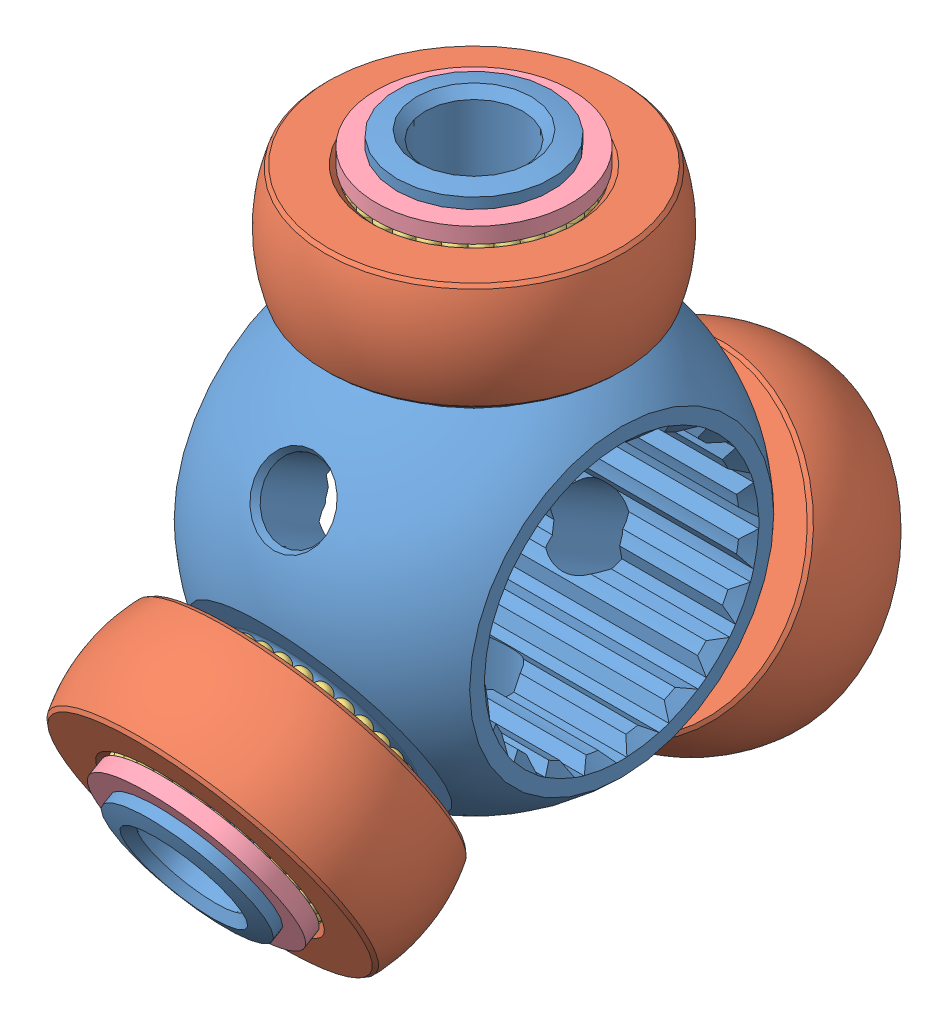
SolidWorks assembly EN-00031-AB-RCV Tripod, configuration Detailed. Lengths in mm.
Overall size (34.45 50.64 55.63).
94 component instances, 4 part files, 0 mates.
Components (placement in the parent):
- FSAE Tripod V2_1^EN-00031-AB-RCV Tripod-1: FSAE Tripod V2_1^EN-00031-AB-RCV Tripod [Default] at (-43.6945 4.946 19.6967) size (34.45 46.11 52.87) (virtual)
- FSAE roller_2451_2^EN-00031-AB-RCV Tripod-2: FSAE roller_2451_2^EN-00031-AB-RCV Tripod [Default] at (-43.6945 -7.4365 41.1438) x (0 0.5 -0.866025) z (1 0 0) size (8.74 25.48 25.48) (virtual)
- FSAE roller_2451_2^EN-00031-AB-RCV Tripod-3: FSAE roller_2451_2^EN-00031-AB-RCV Tripod [Default] at (-43.6945 -7.4365 -1.7504) x (0 0.5 0.866025) z (-1 0 0) size (8.74 25.48 25.48) (virtual)
- FSAE roller_2451_2^EN-00031-AB-RCV Tripod-4: FSAE roller_2451_2^EN-00031-AB-RCV Tripod [Default] at (-43.6945 29.711 19.6967) x (0 -1 0) z (-1 0 0) size (8.74 25.48 25.48) (virtual)
- needle^EN-00031-AB-RCV Tripod-1: needle^EN-00031-AB-RCV Tripod [Default] at (-42.3538 -7.5483 -1.6859) x (1 0 0) z (0 0.5 0.866025) size (1.5 1.5 10.16) (virtual)
- needle^EN-00031-AB-RCV Tripod-2: needle^EN-00031-AB-RCV Tripod [Default] at (-42.3574 -7.2961 -1.8314) x (0.976635 0.186114 -0.107453) z (0 0.5 0.866025) size (1.5 1.5 10.16) (virtual)
- needle^EN-00031-AB-RCV Tripod-3: needle^EN-00031-AB-RCV Tripod [Default] at (-42.4235 -7.0506 -1.9732) x (0.907631 0.363531 -0.209884) z (0 0.5 0.866025) size (1.5 1.5 10.16) (virtual)
- needle^EN-00031-AB-RCV Tripod-4: needle^EN-00031-AB-RCV Tripod [Default] at (-42.5489 -6.823 -2.1046) x (0.796213 0.523959 -0.302508) z (0 0.5 0.866025) size (1.5 1.5 10.16) (virtual)
- needle^EN-00031-AB-RCV Tripod-5: needle^EN-00031-AB-RCV Tripod [Default] at (-42.7279 -6.6242 -2.2194) x (0.647588 0.659903 -0.380995) z (0 0.5 0.866025) size (1.5 1.5 10.16) (virtual)
- needle^EN-00031-AB-RCV Tripod-6: needle^EN-00031-AB-RCV Tripod [Default] at (-42.9521 -6.4632 -2.3123) x (0.468701 0.76501 -0.441678) z (0 0.5 0.866025) size (1.5 1.5 10.16) (virtual)
- needle^EN-00031-AB-RCV Tripod-7: needle^EN-00031-AB-RCV Tripod [Default] at (-43.2109 -6.3478 -2.3789) x (0.267911 0.834367 -0.481722) z (0 0.5 0.866025) size (1.5 1.5 10.16) (virtual)
- needle^EN-00031-AB-RCV Tripod-8: needle^EN-00031-AB-RCV Tripod [Default] at (-43.4924 -6.2833 -2.4162) x (0.054602 0.864733 -0.499254) z (0 0.5 0.866025) size (1.5 1.5 10.16) (virtual)
- needle^EN-00031-AB-RCV Tripod-9: needle^EN-00031-AB-RCV Tripod [Default] at (-43.7833 -6.2726 -2.4224) x (-0.161259 0.854691 -0.493456) z (0 0.5 0.866025) size (1.5 1.5 10.16) (virtual)
- needle^EN-00031-AB-RCV Tripod-10: needle^EN-00031-AB-RCV Tripod [Default] at (-44.07 -6.3163 -2.3971) x (-0.369585 0.804708 -0.464599) z (0 0.5 0.866025) size (1.5 1.5 10.16) (virtual)
- needle^EN-00031-AB-RCV Tripod-11: needle^EN-00031-AB-RCV Tripod [Default] at (-44.3392 -6.4124 -2.3417) x (-0.560639 0.717121 -0.41403) z (0 0.5 0.866025) size (1.5 1.5 10.16) (virtual)
- needle^EN-00031-AB-RCV Tripod-12: needle^EN-00031-AB-RCV Tripod [Default] at (-44.5783 -6.5563 -2.2586) x (-0.725495 0.596023 -0.344114) z (0 0.5 0.866025) size (1.5 1.5 10.16) (virtual)
- needle^EN-00031-AB-RCV Tripod-13: needle^EN-00031-AB-RCV Tripod [Default] at (-44.7761 -6.7413 -2.1517) x (-0.856447 0.447072 -0.258117) z (0 0.5 0.866025) size (1.5 1.5 10.16) (virtual)
- needle^EN-00031-AB-RCV Tripod-14: needle^EN-00031-AB-RCV Tripod [Default] at (-44.9233 -6.9589 -2.0261) x (-0.947378 0.277229 -0.160058) z (0 0.5 0.866025) size (1.5 1.5 10.16) (virtual)
- needle^EN-00031-AB-RCV Tripod-15: needle^EN-00031-AB-RCV Tripod [Default] at (-45.0131 -7.1987 -1.8877) x (-0.994037 0.094432 -0.05452) z (0 0.5 0.866025) size (1.5 1.5 10.16) (virtual)
- needle^EN-00031-AB-RCV Tripod-16: needle^EN-00031-AB-RCV Tripod [Default] at (-45.0413 -7.4497 -1.7428) x (-0.994245 -0.092779 0.053566) z (0 0.5 0.866025) size (1.5 1.5 10.16) (virtual)
- needle^EN-00031-AB-RCV Tripod-17: needle^EN-00031-AB-RCV Tripod [Default] at (-45.0065 -7.7 -1.5982) x (-0.947991 -0.275654 0.159149) z (0 0.5 0.866025) size (1.5 1.5 10.16) (virtual)
- needle^EN-00031-AB-RCV Tripod-18: needle^EN-00031-AB-RCV Tripod [Default] at (-44.9105 -7.9381 -1.4608) x (-0.857437 -0.445647 0.257295) z (0 0.5 0.866025) size (1.5 1.5 10.16) (virtual)
- needle^EN-00031-AB-RCV Tripod-19: needle^EN-00031-AB-RCV Tripod [Default] at (-44.7576 -8.1527 -1.3369) x (-0.726814 -0.594816 0.343417) z (0 0.5 0.866025) size (1.5 1.5 10.16) (virtual)
- needle^EN-00031-AB-RCV Tripod-20: needle^EN-00031-AB-RCV Tripod [Default] at (-44.555 -8.3338 -1.2323) x (-0.562228 -0.716188 0.413491) z (0 0.5 0.866025) size (1.5 1.5 10.16) (virtual)
- needle^EN-00031-AB-RCV Tripod-21: needle^EN-00031-AB-RCV Tripod [Default] at (-44.3122 -8.473 -1.152) x (-0.371368 -0.804092 0.464243) z (0 0.5 0.866025) size (1.5 1.5 10.16) (virtual)
- needle^EN-00031-AB-RCV Tripod-22: needle^EN-00031-AB-RCV Tripod [Default] at (-44.0406 -8.5637 -1.0996) x (-0.163154 -0.854421 0.4933) z (0 0.5 0.866025) size (1.5 1.5 10.16) (virtual)
- needle^EN-00031-AB-RCV Tripod-23: needle^EN-00031-AB-RCV Tripod [Default] at (-43.7528 -8.6018 -1.0776) x (0.052685 -0.864823 0.499306) z (0 0.5 0.866025) size (1.5 1.5 10.16) (virtual)
- needle^EN-00031-AB-RCV Tripod-24: needle^EN-00031-AB-RCV Tripod [Default] at (-43.4622 -8.5854 -1.0871) x (0.266061 -0.834811 0.481978) z (0 0.5 0.866025) size (1.5 1.5 10.16) (virtual)
- needle^EN-00031-AB-RCV Tripod-25: needle^EN-00031-AB-RCV Tripod [Default] at (-43.1825 -8.5153 -1.1275) x (0.467004 -0.765787 0.442128) z (0 0.5 0.866025) size (1.5 1.5 10.16) (virtual)
- needle^EN-00031-AB-RCV Tripod-26: needle^EN-00031-AB-RCV Tripod [Default] at (-42.9268 -8.3949 -1.1971) x (0.646124 -0.660979 0.381616) z (0 0.5 0.866025) size (1.5 1.5 10.16) (virtual)
- needle^EN-00031-AB-RCV Tripod-27: needle^EN-00031-AB-RCV Tripod [Default] at (-42.7069 -8.2296 -1.2925) x (0.79505 -0.525282 0.303272) z (0 0.5 0.866025) size (1.5 1.5 10.16) (virtual)
- needle^EN-00031-AB-RCV Tripod-28: needle^EN-00031-AB-RCV Tripod [Default] at (-42.5332 -8.0272 -1.4093) x (0.906823 -0.365039 0.210755) z (0 0.5 0.866025) size (1.5 1.5 10.16) (virtual)
- needle^EN-00031-AB-RCV Tripod-29: needle^EN-00031-AB-RCV Tripod [Default] at (-42.4137 -7.7973 -1.5421) x (0.97622 -0.187737 0.10839) z (0 0.5 0.866025) size (1.5 1.5 10.16) (virtual)
- needle^EN-00031-AB-RCV Tripod-30: needle^EN-00031-AB-RCV Tripod [Default] at (-42.3538 29.711 19.5676) x (1 0 0) z (0 -1 0) size (1.5 1.5 10.16) (virtual)
- needle^EN-00031-AB-RCV Tripod-31: needle^EN-00031-AB-RCV Tripod [Default] at (-42.3538 -7.3247 41.2084) x (1 0 0) z (0 0.5 -0.866025) size (1.5 1.5 10.16) (virtual)
- needle^EN-00031-AB-RCV Tripod-32: needle^EN-00031-AB-RCV Tripod [Default] at (-42.4137 29.711 19.2801) x (0.97622 0 -0.21678) z (0 -1 0) size (1.5 1.5 10.16) (virtual)
- needle^EN-00031-AB-RCV Tripod-33: needle^EN-00031-AB-RCV Tripod [Default] at (-42.4137 -7.0756 41.3522) x (0.97622 0.187737 0.10839) z (0 0.5 -0.866025) size (1.5 1.5 10.16) (virtual)
- needle^EN-00031-AB-RCV Tripod-34: needle^EN-00031-AB-RCV Tripod [Default] at (-42.5332 29.711 19.0146) x (0.906823 0 -0.421511) z (0 -1 0) size (1.5 1.5 10.16) (virtual)
- needle^EN-00031-AB-RCV Tripod-35: needle^EN-00031-AB-RCV Tripod [Default] at (-42.5332 -6.8457 41.4849) x (0.906823 0.365039 0.210755) z (0 0.5 -0.866025) size (1.5 1.5 10.16) (virtual)
- needle^EN-00031-AB-RCV Tripod-36: needle^EN-00031-AB-RCV Tripod [Default] at (-42.7069 29.711 18.7809) x (0.79505 0 -0.606544) z (0 -1 0) size (1.5 1.5 10.16) (virtual)
- needle^EN-00031-AB-RCV Tripod-37: needle^EN-00031-AB-RCV Tripod [Default] at (-42.7069 -6.6434 41.6017) x (0.79505 0.525282 0.303272) z (0 0.5 -0.866025) size (1.5 1.5 10.16) (virtual)
- needle^EN-00031-AB-RCV Tripod-38: needle^EN-00031-AB-RCV Tripod [Default] at (-42.9268 29.711 18.5901) x (0.646124 0 -0.763232) z (0 -1 0) size (1.5 1.5 10.16) (virtual)
- needle^EN-00031-AB-RCV Tripod-39: needle^EN-00031-AB-RCV Tripod [Default] at (-42.9268 -6.4781 41.6972) x (0.646124 0.660979 0.381616) z (0 0.5 -0.866025) size (1.5 1.5 10.16) (virtual)
- needle^EN-00031-AB-RCV Tripod-40: needle^EN-00031-AB-RCV Tripod [Default] at (-43.1825 29.711 18.4509) x (0.467004 0 -0.884255) z (0 -1 0) size (1.5 1.5 10.16) (virtual)
- needle^EN-00031-AB-RCV Tripod-41: needle^EN-00031-AB-RCV Tripod [Default] at (-43.1825 -6.3576 41.7667) x (0.467004 0.765787 0.442128) z (0 0.5 -0.866025) size (1.5 1.5 10.16) (virtual)
- needle^EN-00031-AB-RCV Tripod-42: needle^EN-00031-AB-RCV Tripod [Default] at (-43.4622 29.711 18.37) x (0.266061 0 -0.963956) z (0 -1 0) size (1.5 1.5 10.16) (virtual)
- needle^EN-00031-AB-RCV Tripod-43: needle^EN-00031-AB-RCV Tripod [Default] at (-43.4622 -6.2875 41.8072) x (0.266061 0.834811 0.481978) z (0 0.5 -0.866025) size (1.5 1.5 10.16) (virtual)
- needle^EN-00031-AB-RCV Tripod-44: needle^EN-00031-AB-RCV Tripod [Default] at (-43.7528 29.711 18.3511) x (0.052685 0 -0.998611) z (0 -1 0) size (1.5 1.5 10.16) (virtual)
- needle^EN-00031-AB-RCV Tripod-45: needle^EN-00031-AB-RCV Tripod [Default] at (-43.7528 -6.2711 41.8166) x (0.052685 0.864823 0.499306) z (0 0.5 -0.866025) size (1.5 1.5 10.16) (virtual)
- needle^EN-00031-AB-RCV Tripod-46: needle^EN-00031-AB-RCV Tripod [Default] at (-44.0406 29.711 18.3951) x (-0.163154 0 -0.986601) z (0 -1 0) size (1.5 1.5 10.16) (virtual)
- needle^EN-00031-AB-RCV Tripod-47: needle^EN-00031-AB-RCV Tripod [Default] at (-44.0406 -6.3092 41.7947) x (-0.163154 0.854421 0.4933) z (0 0.5 -0.866025) size (1.5 1.5 10.16) (virtual)
- needle^EN-00031-AB-RCV Tripod-48: needle^EN-00031-AB-RCV Tripod [Default] at (-44.3122 29.711 18.4999) x (-0.371368 0 -0.928486) z (0 -1 0) size (1.5 1.5 10.16) (virtual)
- needle^EN-00031-AB-RCV Tripod-49: needle^EN-00031-AB-RCV Tripod [Default] at (-44.3122 -6.4 41.7423) x (-0.371368 0.804092 0.464243) z (0 0.5 -0.866025) size (1.5 1.5 10.16) (virtual)
- needle^EN-00031-AB-RCV Tripod-50: needle^EN-00031-AB-RCV Tripod [Default] at (-44.555 29.711 18.6606) x (-0.562228 0 -0.826982) z (0 -1 0) size (1.5 1.5 10.16) (virtual)
- needle^EN-00031-AB-RCV Tripod-51: needle^EN-00031-AB-RCV Tripod [Default] at (-44.555 -6.5392 41.6619) x (-0.562228 0.716188 0.413491) z (0 0.5 -0.866025) size (1.5 1.5 10.16) (virtual)
- needle^EN-00031-AB-RCV Tripod-52: needle^EN-00031-AB-RCV Tripod [Default] at (-44.7576 29.711 18.8697) x (-0.726814 0 -0.686834) z (0 -1 0) size (1.5 1.5 10.16) (virtual)
- needle^EN-00031-AB-RCV Tripod-53: needle^EN-00031-AB-RCV Tripod [Default] at (-44.7576 -6.7203 41.5573) x (-0.726814 0.594816 0.343417) z (0 0.5 -0.866025) size (1.5 1.5 10.16) (virtual)
- needle^EN-00031-AB-RCV Tripod-54: needle^EN-00031-AB-RCV Tripod [Default] at (-44.9105 29.711 19.1175) x (-0.857437 0 -0.514589) z (0 -1 0) size (1.5 1.5 10.16) (virtual)
- needle^EN-00031-AB-RCV Tripod-55: needle^EN-00031-AB-RCV Tripod [Default] at (-44.9105 -6.9349 41.4334) x (-0.857437 0.445647 0.257295) z (0 0.5 -0.866025) size (1.5 1.5 10.16) (virtual)
- needle^EN-00031-AB-RCV Tripod-56: needle^EN-00031-AB-RCV Tripod [Default] at (-45.0065 29.711 19.3924) x (-0.947991 0 -0.318298) z (0 -1 0) size (1.5 1.5 10.16) (virtual)
- needle^EN-00031-AB-RCV Tripod-57: needle^EN-00031-AB-RCV Tripod [Default] at (-45.0065 -7.1729 41.296) x (-0.947991 0.275654 0.159149) z (0 0.5 -0.866025) size (1.5 1.5 10.16) (virtual)
- needle^EN-00031-AB-RCV Tripod-58: needle^EN-00031-AB-RCV Tripod [Default] at (-45.0413 29.711 19.6814) x (-0.994245 0 -0.107132) z (0 -1 0) size (1.5 1.5 10.16) (virtual)
- needle^EN-00031-AB-RCV Tripod-59: needle^EN-00031-AB-RCV Tripod [Default] at (-45.0413 -7.4232 41.1515) x (-0.994245 0.092779 0.053566) z (0 0.5 -0.866025) size (1.5 1.5 10.16) (virtual)
- needle^EN-00031-AB-RCV Tripod-60: needle^EN-00031-AB-RCV Tripod [Default] at (-45.0131 29.711 19.9712) x (-0.994037 0 0.10904) z (0 -1 0) size (1.5 1.5 10.16) (virtual)
- needle^EN-00031-AB-RCV Tripod-61: needle^EN-00031-AB-RCV Tripod [Default] at (-45.0131 -7.6742 41.0066) x (-0.994037 -0.094432 -0.05452) z (0 0.5 -0.866025) size (1.5 1.5 10.16) (virtual)
- needle^EN-00031-AB-RCV Tripod-62: needle^EN-00031-AB-RCV Tripod [Default] at (-44.9233 29.711 20.2482) x (-0.947378 0 0.320117) z (0 -1 0) size (1.5 1.5 10.16) (virtual)
- needle^EN-00031-AB-RCV Tripod-63: needle^EN-00031-AB-RCV Tripod [Default] at (-44.9233 -7.914 40.8681) x (-0.947378 -0.277229 -0.160058) z (0 0.5 -0.866025) size (1.5 1.5 10.16) (virtual)
- needle^EN-00031-AB-RCV Tripod-64: needle^EN-00031-AB-RCV Tripod [Default] at (-44.7761 29.711 20.4994) x (-0.856447 0 0.516234) z (0 -1 0) size (1.5 1.5 10.16) (virtual)
- needle^EN-00031-AB-RCV Tripod-65: needle^EN-00031-AB-RCV Tripod [Default] at (-44.7761 -8.1316 40.7425) x (-0.856447 -0.447072 -0.258117) z (0 0.5 -0.866025) size (1.5 1.5 10.16) (virtual)
- needle^EN-00031-AB-RCV Tripod-66: needle^EN-00031-AB-RCV Tripod [Default] at (-44.5783 29.711 20.7131) x (-0.725495 0 0.688228) z (0 -1 0) size (1.5 1.5 10.16) (virtual)
- needle^EN-00031-AB-RCV Tripod-67: needle^EN-00031-AB-RCV Tripod [Default] at (-44.5783 -8.3166 40.6357) x (-0.725495 -0.596023 -0.344114) z (0 0.5 -0.866025) size (1.5 1.5 10.16) (virtual)
- needle^EN-00031-AB-RCV Tripod-68: needle^EN-00031-AB-RCV Tripod [Default] at (-44.3392 29.711 20.8792) x (-0.560639 0 0.82806) z (0 -1 0) size (1.5 1.5 10.16) (virtual)
- needle^EN-00031-AB-RCV Tripod-69: needle^EN-00031-AB-RCV Tripod [Default] at (-44.3392 -8.4606 40.5526) x (-0.560639 -0.717121 -0.41403) z (0 0.5 -0.866025) size (1.5 1.5 10.16) (virtual)
- needle^EN-00031-AB-RCV Tripod-70: needle^EN-00031-AB-RCV Tripod [Default] at (-44.07 29.711 20.9902) x (-0.369585 0 0.929197) z (0 -1 0) size (1.5 1.5 10.16) (virtual)
- needle^EN-00031-AB-RCV Tripod-71: needle^EN-00031-AB-RCV Tripod [Default] at (-44.07 -8.5566 40.4971) x (-0.369585 -0.804708 -0.464599) z (0 0.5 -0.866025) size (1.5 1.5 10.16) (virtual)
- needle^EN-00031-AB-RCV Tripod-72: needle^EN-00031-AB-RCV Tripod [Default] at (-43.7833 29.711 21.0407) x (-0.161259 0 0.986912) z (0 -1 0) size (1.5 1.5 10.16) (virtual)
- needle^EN-00031-AB-RCV Tripod-73: needle^EN-00031-AB-RCV Tripod [Default] at (-43.7833 -8.6003 40.4719) x (-0.161259 -0.854691 -0.493456) z (0 0.5 -0.866025) size (1.5 1.5 10.16) (virtual)
- needle^EN-00031-AB-RCV Tripod-74: needle^EN-00031-AB-RCV Tripod [Default] at (-43.4924 29.711 21.0283) x (0.054602 0 0.998508) z (0 -1 0) size (1.5 1.5 10.16) (virtual)
- needle^EN-00031-AB-RCV Tripod-75: needle^EN-00031-AB-RCV Tripod [Default] at (-43.4924 -8.5897 40.478) x (0.054602 -0.864733 -0.499254) z (0 0.5 -0.866025) size (1.5 1.5 10.16) (virtual)
- needle^EN-00031-AB-RCV Tripod-76: needle^EN-00031-AB-RCV Tripod [Default] at (-43.2109 29.711 20.9538) x (0.267911 0 0.963444) z (0 -1 0) size (1.5 1.5 10.16) (virtual)
- needle^EN-00031-AB-RCV Tripod-77: needle^EN-00031-AB-RCV Tripod [Default] at (-43.2109 -8.5251 40.5153) x (0.267911 -0.834367 -0.481722) z (0 0.5 -0.866025) size (1.5 1.5 10.16) (virtual)
- needle^EN-00031-AB-RCV Tripod-78: needle^EN-00031-AB-RCV Tripod [Default] at (-42.9521 29.711 20.8205) x (0.468701 0 0.883357) z (0 -1 0) size (1.5 1.5 10.16) (virtual)
- needle^EN-00031-AB-RCV Tripod-79: needle^EN-00031-AB-RCV Tripod [Default] at (-42.9521 -8.4097 40.582) x (0.468701 -0.76501 -0.441678) z (0 0.5 -0.866025) size (1.5 1.5 10.16) (virtual)
- needle^EN-00031-AB-RCV Tripod-80: needle^EN-00031-AB-RCV Tripod [Default] at (-42.7279 29.711 20.6347) x (0.647588 0 0.761991) z (0 -1 0) size (1.5 1.5 10.16) (virtual)
- needle^EN-00031-AB-RCV Tripod-81: needle^EN-00031-AB-RCV Tripod [Default] at (-42.7279 -8.2488 40.6749) x (0.647588 -0.659903 -0.380995) z (0 0.5 -0.866025) size (1.5 1.5 10.16) (virtual)
- needle^EN-00031-AB-RCV Tripod-82: needle^EN-00031-AB-RCV Tripod [Default] at (-42.5489 29.711 20.4051) x (0.796213 0 0.605016) z (0 -1 0) size (1.5 1.5 10.16) (virtual)
- needle^EN-00031-AB-RCV Tripod-83: needle^EN-00031-AB-RCV Tripod [Default] at (-42.5489 -8.0499 40.7897) x (0.796213 -0.523959 -0.302508) z (0 0.5 -0.866025) size (1.5 1.5 10.16) (virtual)
- needle^EN-00031-AB-RCV Tripod-84: needle^EN-00031-AB-RCV Tripod [Default] at (-42.4235 29.711 20.1423) x (0.907631 0 0.419769) z (0 -1 0) size (1.5 1.5 10.16) (virtual)
- needle^EN-00031-AB-RCV Tripod-85: needle^EN-00031-AB-RCV Tripod [Default] at (-42.4235 -7.8224 40.921) x (0.907631 -0.363531 -0.209884) z (0 0.5 -0.866025) size (1.5 1.5 10.16) (virtual)
- needle^EN-00031-AB-RCV Tripod-86: needle^EN-00031-AB-RCV Tripod [Default] at (-42.3574 29.711 19.8588) x (0.976635 0 0.214906) z (0 -1 0) size (1.5 1.5 10.16) (virtual)
- needle^EN-00031-AB-RCV Tripod-87: needle^EN-00031-AB-RCV Tripod [Default] at (-42.3574 -7.5768 41.0628) x (0.976635 -0.186114 -0.107453) z (0 0.5 -0.866025) size (1.5 1.5 10.16) (virtual)
- Tripod Retainer^EN-00031-AB-RCV Tripod-1: Tripod Retainer^EN-00031-AB-RCV Tripod [Default] at (-43.6945 -8.0715 -2.8502) x (0.973299 0.198788 -0.11477) z (0 0.5 0.866025) size (15.88 15.88 1.27) (virtual)
- Tripod Retainer^EN-00031-AB-RCV Tripod-2: Tripod Retainer^EN-00031-AB-RCV Tripod [Default] at (-43.6945 -8.0715 42.2437) x (0.973299 -0.198788 -0.11477) z (0 0.5 -0.866025) size (15.88 15.88 1.27) (virtual)
- Tripod Retainer^EN-00031-AB-RCV Tripod-3: Tripod Retainer^EN-00031-AB-RCV Tripod [Default] at (-43.6945 30.981 19.6967) x (0.973299 0 0.229541) z (0 -1 0) size (15.88 15.88 1.27) (virtual)
